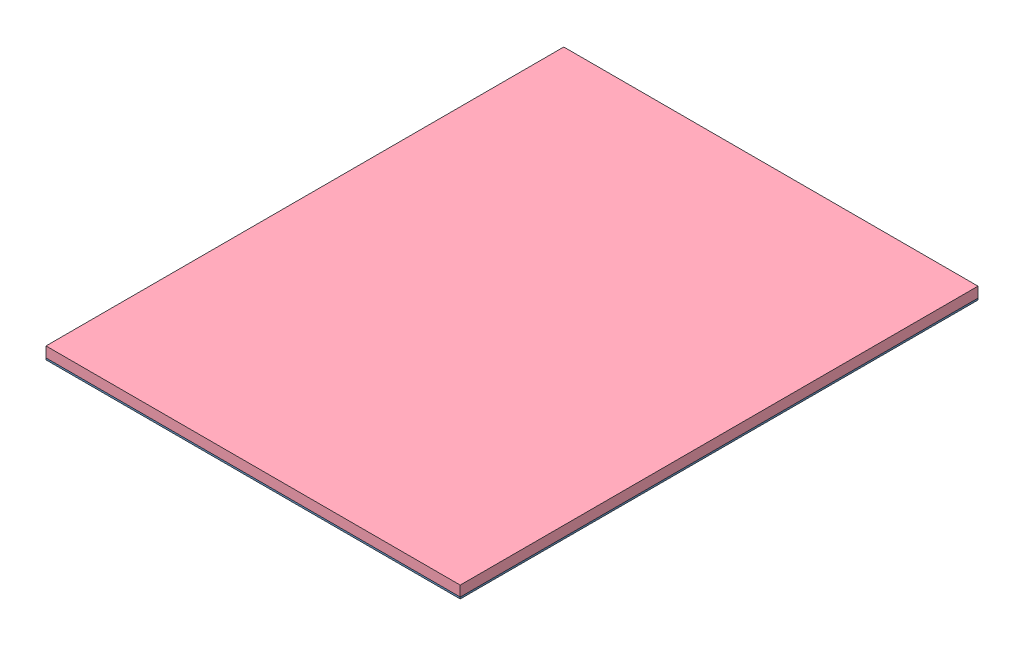
SolidWorks assembly SolarPanel_000, configuration Default. Lengths in mm.
Overall size (120 22.8 150).
58 component instances, 4 part files, 12 mates.
Components (placement in the parent):
- SolarPanel_001-1: SolarPanel_001 [Default] at (-4.4954 26.7345 -9.5009) size (120 20.08 150)
- SolarPanel_002-1: SolarPanel_002 [Default] at (-30.4954 27.2345 -70.5009) size (50 0.18 8)
- SolarPanel_002-2: SolarPanel_002 [Default] at (-30.4954 27.2345 -61.0009) size (50 0.18 8)
- SolarPanel_002-3: SolarPanel_002 [Default] at (-30.4954 27.2345 -51.5009) size (50 0.18 8)
- SolarPanel_002-4: SolarPanel_002 [Default] at (-30.4954 27.2345 -42.0009) size (50 0.18 8)
- SolarPanel_002-5: SolarPanel_002 [Default] at (-30.4954 27.2345 -32.5009) size (50 0.18 8)
- SolarPanel_002-6: SolarPanel_002 [Default] at (-30.4954 27.2345 -23.0009) size (50 0.18 8)
- SolarPanel_002-7: SolarPanel_002 [Default] at (-30.4954 27.2345 -13.5009) size (50 0.18 8)
- SolarPanel_002-8: SolarPanel_002 [Default] at (-30.4954 27.2345 -4.0009) size (50 0.18 8)
- SolarPanel_002-9: SolarPanel_002 [Default] at (-30.4954 27.2345 5.4991) size (50 0.18 8)
- SolarPanel_002-10: SolarPanel_002 [Default] at (-30.4954 27.2345 14.9991) size (50 0.18 8)
- SolarPanel_002-11: SolarPanel_002 [Default] at (-30.4954 27.2345 24.4991) size (50 0.18 8)
- SolarPanel_002-12: SolarPanel_002 [Default] at (-30.4954 27.2345 33.9991) size (50 0.18 8)
- SolarPanel_002-13: SolarPanel_002 [Default] at (-30.4954 27.2345 43.4991) size (50 0.18 8)
- SolarPanel_002-14: SolarPanel_002 [Default] at (-30.4954 27.2345 52.9991) size (50 0.18 8)
- SolarPanel_002-15: SolarPanel_002 [Default] at (20.5046 27.2345 -70.5009) size (50 0.18 8)
- SolarPanel_002-16: SolarPanel_002 [Default] at (20.5046 27.2345 -61.0009) size (50 0.18 8)
- SolarPanel_002-17: SolarPanel_002 [Default] at (20.5046 27.2345 -51.5009) size (50 0.18 8)
- SolarPanel_002-18: SolarPanel_002 [Default] at (20.5046 27.2345 -42.0009) size (50 0.18 8)
- SolarPanel_002-19: SolarPanel_002 [Default] at (20.5046 27.2345 -32.5009) size (50 0.18 8)
- SolarPanel_002-20: SolarPanel_002 [Default] at (20.5046 27.2345 -23.0009) size (50 0.18 8)
- SolarPanel_002-21: SolarPanel_002 [Default] at (20.5046 27.2345 -13.5009) size (50 0.18 8)
- SolarPanel_002-22: SolarPanel_002 [Default] at (20.5046 27.2345 -4.0009) size (50 0.18 8)
- SolarPanel_002-23: SolarPanel_002 [Default] at (20.5046 27.2345 5.4991) size (50 0.18 8)
- SolarPanel_002-24: SolarPanel_002 [Default] at (20.5046 27.2345 14.9991) size (50 0.18 8)
- SolarPanel_002-25: SolarPanel_002 [Default] at (20.5046 27.2345 24.4991) size (50 0.18 8)
- SolarPanel_002-26: SolarPanel_002 [Default] at (20.5046 27.2345 33.9991) size (50 0.18 8)
- SolarPanel_002-27: SolarPanel_002 [Default] at (20.5046 27.2345 43.4991) size (50 0.18 8)
- SolarPanel_002-28: SolarPanel_002 [Default] at (20.5046 27.2345 52.9991) size (50 0.18 8)
- SolarPanel_003-1: SolarPanel_003 [Default] at (-30.3704 27.4145 -64.5009) size (1.5 0.01 4)
- SolarPanel_003-2: SolarPanel_003 [Default] at (-30.3704 27.4145 -55.0009) size (1.5 0.01 4)
- SolarPanel_003-3: SolarPanel_003 [Default] at (-30.3704 27.4145 -45.5009) size (1.5 0.01 4)
- SolarPanel_003-4: SolarPanel_003 [Default] at (-30.3704 27.4145 -36.0009) size (1.5 0.01 4)
- SolarPanel_003-5: SolarPanel_003 [Default] at (-30.3704 27.4145 -26.5009) size (1.5 0.01 4)
- SolarPanel_003-6: SolarPanel_003 [Default] at (-30.3704 27.4145 -17.0009) size (1.5 0.01 4)
- SolarPanel_003-7: SolarPanel_003 [Default] at (-30.3704 27.4145 -7.5009) size (1.5 0.01 4)
- SolarPanel_003-8: SolarPanel_003 [Default] at (-30.3704 27.4145 1.9991) size (1.5 0.01 4)
- SolarPanel_003-9: SolarPanel_003 [Default] at (-30.3704 27.4145 11.4991) size (1.5 0.01 4)
- SolarPanel_003-10: SolarPanel_003 [Default] at (-30.3704 27.4145 20.9991) size (1.5 0.01 4)
- SolarPanel_003-11: SolarPanel_003 [Default] at (-30.3704 27.4145 30.4991) size (1.5 0.01 4)
- SolarPanel_003-12: SolarPanel_003 [Default] at (-30.3704 27.4145 39.9991) size (1.5 0.01 4)
- SolarPanel_003-13: SolarPanel_003 [Default] at (-30.3704 27.4145 49.4991) size (1.5 0.01 4)
- SolarPanel_003-14: SolarPanel_003 [Default] at (-30.3704 27.4145 58.9991) size (1.5 0.01 4)
- SolarPanel_003-15: SolarPanel_003 [Default] at (20.3796 27.4145 -72.5009) size (1.5 0.01 4)
- SolarPanel_003-16: SolarPanel_003 [Default] at (20.3796 27.4145 -63.0009) size (1.5 0.01 4)
- SolarPanel_003-17: SolarPanel_003 [Default] at (20.3796 27.4145 -53.5009) size (1.5 0.01 4)
- SolarPanel_003-18: SolarPanel_003 [Default] at (20.3796 27.4145 -44.0009) size (1.5 0.01 4)
- SolarPanel_003-19: SolarPanel_003 [Default] at (20.3796 27.4145 -34.5009) size (1.5 0.01 4)
- SolarPanel_003-20: SolarPanel_003 [Default] at (20.3796 27.4145 -25.0009) size (1.5 0.01 4)
- SolarPanel_003-21: SolarPanel_003 [Default] at (20.3796 27.4145 -15.5009) size (1.5 0.01 4)
- SolarPanel_003-22: SolarPanel_003 [Default] at (20.3796 27.4145 -6.0009) size (1.5 0.01 4)
- SolarPanel_003-23: SolarPanel_003 [Default] at (20.3796 27.4145 3.4991) size (1.5 0.01 4)
- SolarPanel_003-24: SolarPanel_003 [Default] at (20.3796 27.4145 12.9991) size (1.5 0.01 4)
- SolarPanel_003-25: SolarPanel_003 [Default] at (20.3796 27.4145 22.4991) size (1.5 0.01 4)
- SolarPanel_003-26: SolarPanel_003 [Default] at (20.3796 27.4145 31.9991) size (1.5 0.01 4)
- SolarPanel_003-27: SolarPanel_003 [Default] at (20.3796 27.4145 41.4991) size (1.5 0.01 4)
- SolarPanel_003-28: SolarPanel_003 [Default] at (20.3796 27.4145 50.9991) size (1.5 0.01 4)
- SolarPanel_004-1: SolarPanel_004 [Default] at (-4.4954 27.2345 -9.5009) size (120 3 150)
Mates (geometry in assembly coordinates):
- Coincident1: coincident: plane of SolarPanel_001-1 through (-4.4954 27.2345 -9.5009) normal (0 1 0); plane of SolarPanel_002-1 through (-30.4954 27.2345 -70.5009) normal (0 -1 0)
- Distance1: distance = 9 mm: plane of SolarPanel_002-1 through (-55.4954 27.4145 -74.5009) normal (-1 0 0); plane of SolarPanel_001-1 through (-64.4954 27.2345 -84.5009) normal (-1 0 0)
- Distance2: distance = 10 mm: plane of SolarPanel_001-1 through (-64.4954 27.2345 -84.5009) normal (0 0 -1); plane of SolarPanel_002-1 through (-55.4954 27.4145 -74.5009) normal (0 0 -1)
- Coincident5: coincident: plane of SolarPanel_002-2 through (-30.4954 27.4145 -61.0009) normal (0 1 0); plane of SolarPanel_003-1 through (-30.3704 27.4145 -64.5009) normal (0 -1 0)
- Coincident6: coincident: line of SolarPanel_002-1 through (-55.4954 27.4145 -66.5009) axis (1 0 0); plane of SolarPanel_003-1 through (-31.1204 27.4245 -66.5009) normal (0 0 -1)
- Distance3: distance = 24.375 mm: line of SolarPanel_002-2 through (-55.4954 27.4145 -65.0009) axis (0 0 1); line of SolarPanel_003-1 through (-31.1204 27.4245 -66.5009) axis (0 0 1)
- Coincident8: coincident: plane of SolarPanel_002-15 through (20.5046 27.4145 -70.5009) normal (0 1 0); line of SolarPanel_003-15 through (21.1296 27.4145 -70.5009) axis (0 0 -1)
- Distance4: distance = 24.375 mm: plane of SolarPanel_003-15 through (21.1296 27.4245 -74.5009) normal (1 0 0); plane of SolarPanel_002-15 through (45.5046 27.4145 -74.5009) normal (1 0 0)
- Coincident10: coincident: plane of SolarPanel_002-15 through (-4.4954 27.4145 -74.5009) normal (0 0 -1); line of SolarPanel_003-15 through (21.1296 27.4245 -74.5009) axis (-1 0 0)
- Coincident11: coincident: plane of SolarPanel_001-1 through (-4.4954 27.2345 -9.5009) normal (0 1 0); plane of SolarPanel_004-1 through (-4.4954 27.2345 -9.5009) normal (0 -1 0)
- Coincident12: coincident: plane of SolarPanel_001-1 through (-64.4954 27.2345 -84.5009) normal (-1 0 0); plane of SolarPanel_004-1 through (-64.4954 30.2345 -84.5009) normal (-1 0 0)
- Coincident13: coincident: plane of SolarPanel_001-1 through (-64.4954 27.2345 -84.5009) normal (0 0 -1); plane of SolarPanel_004-1 through (-64.4954 30.2345 -84.5009) normal (0 0 -1)
